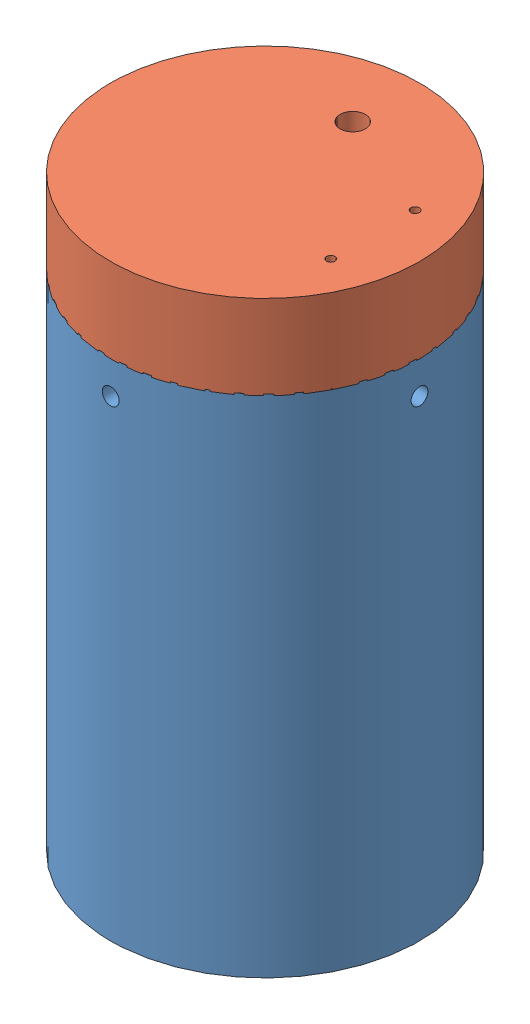
SolidWorks assembly Prototype assembly, configuration Default. Lengths in mm.
Overall size (93.22 177.39 93.22).
2 component instances, 2 part files, 2 mates.
Components (placement in the parent):
- Designed for tube prototype 2-1: Designed for tube prototype 2 [Default] at (-197.9017 -6.0269 -63.1383) size (93.22 152.4 93.22)
- Designed for tube prototype 2b-1: Designed for tube prototype 2b [Default] at (-197.9017 145.961 -63.1383) x (0 0 1) z (-1 0 0) size (93.22 25.4 93.22)
Mates (geometry in assembly coordinates):
- Concentric1: concentric: cylinder of Designed for tube prototype 2-1 through (-165.3897 133.6731 -50.4383) axis (0 1 0) radius 1.27; cylinder of Designed for tube prototype 2b-1 through (-165.3897 145.961 -50.4383) axis (0 1 0) radius 1.27
- Concentric2: concentric: cylinder of Designed for tube prototype 2-1 through (-165.3897 133.6731 -75.8383) axis (0 1 0) radius 1.27; cylinder of Designed for tube prototype 2b-1 through (-165.3897 145.961 -75.8383) axis (0 1 0) radius 1.27
